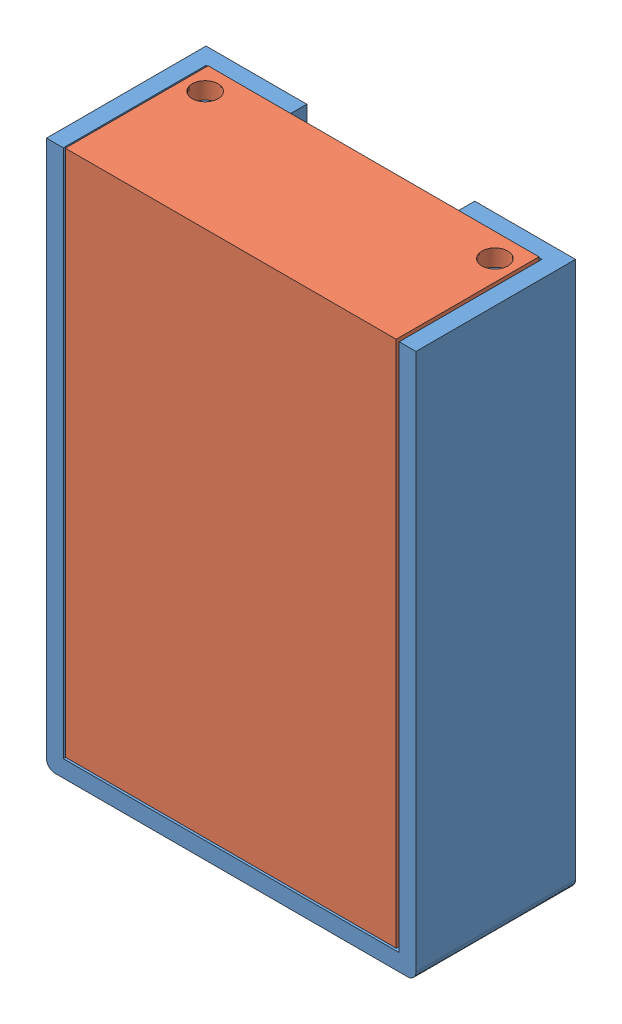
SolidWorks assembly Montagem2, configuration Valor predeterminado. Lengths in mm.
Overall size (44 65.09 19.01).
2 component instances, 2 part files, 0 mates.
Components (placement in the parent):
- suporteRFDI-1: suporteRFDI [Valor predeterminado] at (21.6073 64.4675 42.1658) x (1 0 0) z (0 -1 0) size (44 19 65)
- tampaSuporteRFDI-1: tampaSuporteRFDI [Valor predeterminado] at (21.5608 34.0574 58.2731) x (-1 0 0) z (0 0 -1) size (39.4 62.8 17)
